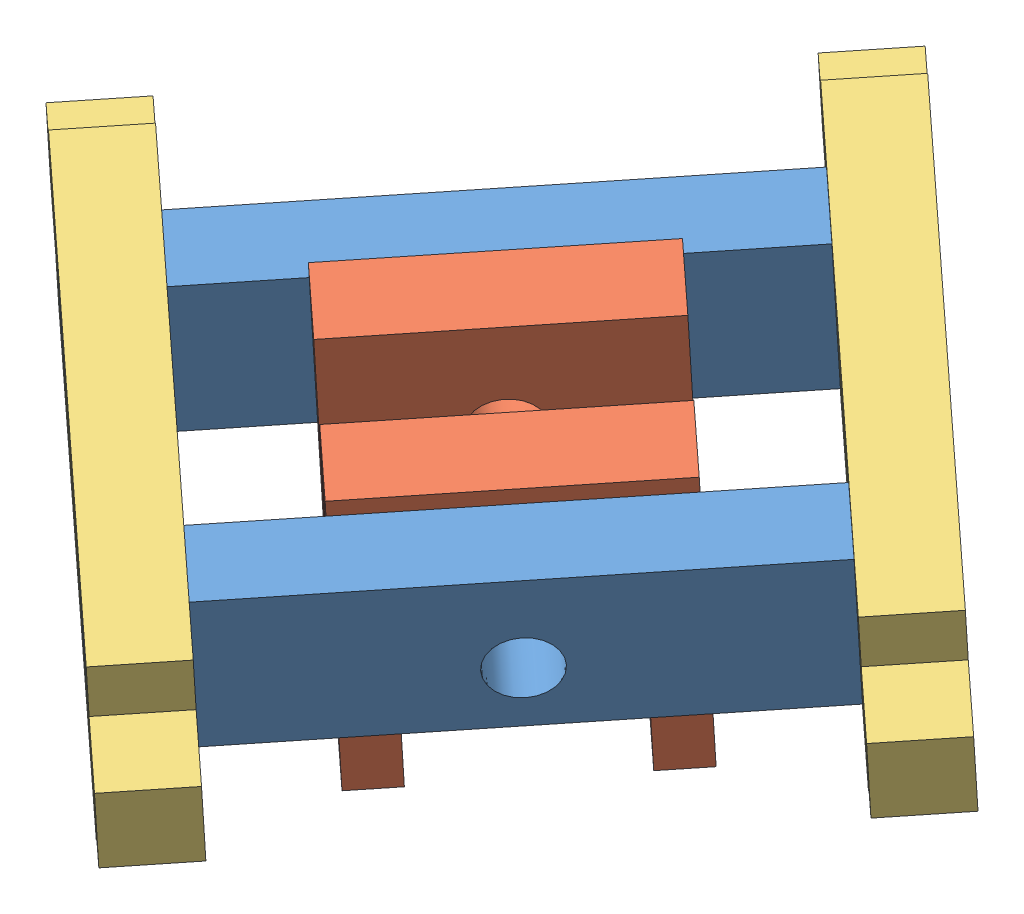
SolidWorks assembly actuatorAttachmentAssembly, configuration Default. Lengths in mm.
Overall size (63.61 26.79 63.52).
6 component instances, 3 part files, 13 mates.
Components (placement in the parent):
- connectorToSpacerA-1: connectorToSpacerA [Default] at (-18.5996 -18.2759 71.6177) x (0.675961 0.049123 -0.735298) z (0.729837 -0.1828 0.658728) size (42.3 10 5.15)
- connectorToSpacerA-2: connectorToSpacerA [Default] at (-3.1636 -22.1422 85.5498) x (0.675961 0.049123 -0.735298) z (0.729837 -0.1828 0.658728) size (42.3 10 5.15)
- spacerA-2: spacerA [Default] at (8.2811 -27.4929 54.9137) x (-0.675961 -0.049123 0.735298) z (-0.729837 0.1828 -0.658728) size (18 20 5.15)
- spacerA-3: spacerA [Default] at (0.2739 -29.4191 71.9038) x (0.675961 0.049123 -0.735298) z (0.729837 -0.1828 0.658728) size (18 20 5.15)
- connectorToMidPlatesAndConnector-3: connectorToMidPlatesAndConnector [Default] at (-22.5188 -17.1769 61.0842) x (0.729837 -0.1828 0.658728) z (-0.675961 -0.049123 0.735298) size (46.3 12 5.15)
- connectorToMidPlatesAndConnector-4: connectorToMidPlatesAndConnector [Default] at (2.5931 -15.3519 33.7679) x (0.729837 -0.1828 0.658728) z (-0.675961 -0.049123 0.735298) size (46.3 12 5.15)
Mates (geometry in assembly coordinates):
- Coincident1: coincident: line of connectorToSpacerA-1 through (-11.3597 -18.9644 71.2234) axis (0.675961 0.049123 -0.735298); line of spacerA-2 through (3.41 -17.891 55.1571) axis (-0.675961 -0.049123 0.735298)
- Concentric1: concentric: cylinder of connectorToSpacerA-1 through (-3.9962 -13.3167 56.8141) axis (0.729837 -0.1828 0.658728) radius 2.0675; cylinder of spacerA-2 through (3.5211 -15.1995 63.599) axis (-0.729837 0.1828 -0.658728) radius 2.0675
- Concentric2: concentric: cylinder of connectorToSpacerA-2 through (11.4398 -17.1829 70.7462) axis (0.729837 -0.1828 0.658728) radius 2.0675; cylinder of spacerA-3 through (7.6812 -16.2415 67.3538) axis (0.729837 -0.1828 0.658728) radius 2.0675
- Coincident2: coincident: line of connectorToSpacerA-2 through (0.3176 -21.8892 81.763) axis (0.675961 0.049123 -0.735298); line of spacerA-3 through (6.9759 -21.4053 74.5203) axis (0.675961 0.049123 -0.735298)
- Coincident3: coincident: line of connectorToSpacerA-2 through (1.3682 -15.6455 90.1498) axis (-0.102053 -0.981922 -0.159418); line of connectorToMidPlatesAndConnector-3 through (0.8426 -20.7024 89.3288) axis (0.102053 0.981922 0.159418)
- Coincident4: coincident: line of connectorToSpacerA-2 through (1.3682 -15.6455 90.1498) axis (-0.729837 0.1828 -0.658728); line of connectorToMidPlatesAndConnector-3 through (1.3682 -15.6455 90.1498) axis (-0.729837 0.1828 -0.658728)
- Coincident5: coincident: line of connectorToSpacerA-1 through (-14.0679 -11.7793 76.2177) axis (-0.729837 0.1828 -0.658728); line of connectorToMidPlatesAndConnector-3 through (-14.0679 -11.7793 76.2177) axis (-0.729837 0.1828 -0.658728)
- Coincident6: coincident: line of connectorToSpacerA-1 through (-14.0679 -11.7793 76.2177) axis (-0.102053 -0.981922 -0.159418); line of connectorToMidPlatesAndConnector-3 through (-14.5935 -16.8362 75.3967) axis (0.102053 0.981922 0.159418)
- Coincident7: coincident: line of connectorToSpacerA-1 through (10.241 -13.8169 40.9012) axis (0.102053 0.981922 0.159418); line of connectorToMidPlatesAndConnector-4 through (10.7666 -8.76 41.7222) axis (-0.102053 -0.981922 -0.159418)
- Coincident8: coincident: line of connectorToSpacerA-1 through (14.5253 -9.7014 45.1146) axis (-0.729837 0.1828 -0.658728); line of connectorToMidPlatesAndConnector-4 through (14.5253 -9.7014 45.1146) axis (-0.729837 0.1828 -0.658728)
- Lock1: lock: unknown of connectorToSpacerA-1; unknown of connectorToMidPlatesAndConnector-4
- Lock2: lock: unknown of connectorToSpacerA-1; unknown of connectorToMidPlatesAndConnector-3
- Concentric3: concentric: circle of spacerA-2; cylinder of spacerA-3 through (7.6812 -16.2415 67.3538) axis (0.729837 -0.1828 0.658728) radius 2.0675
